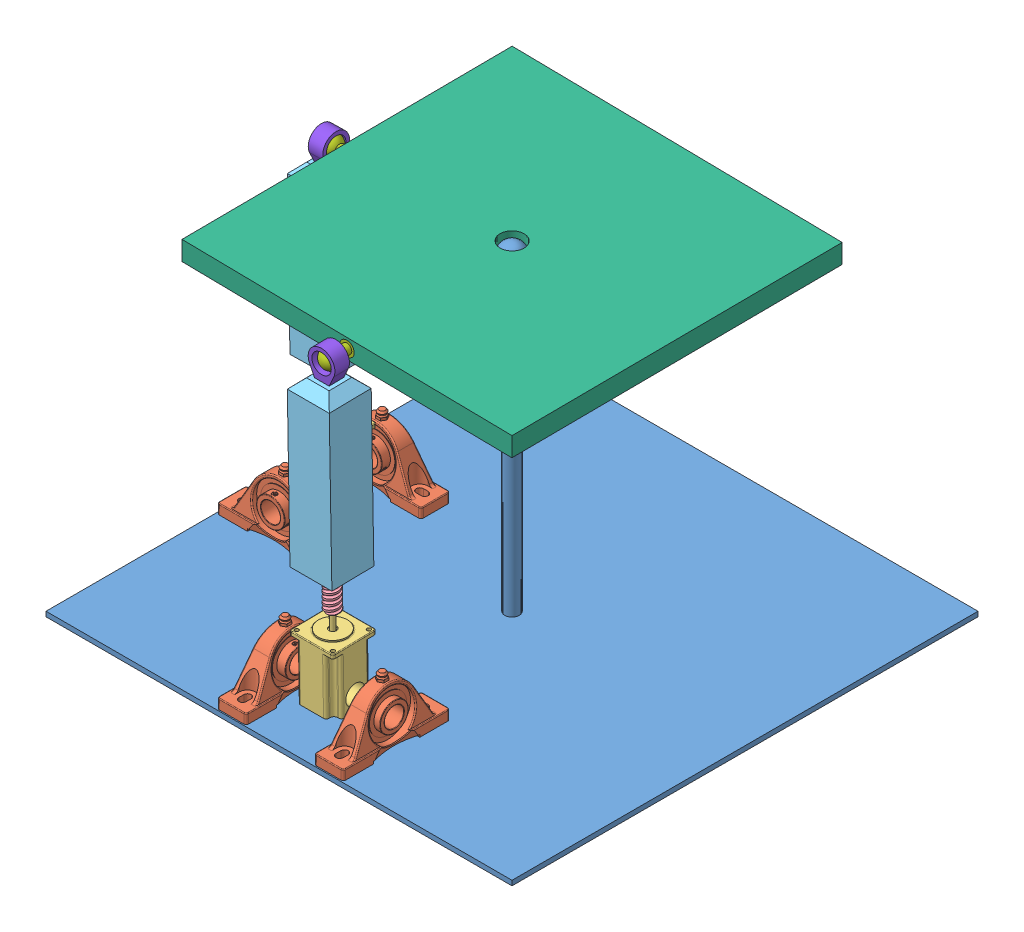
SolidWorks assembly vertical_Assem, configuration Default. Lengths in mm.
Overall size (609.6 435.03 609.6).
16 component instances, 8 part files, 45 mates.
Components (placement in the parent):
- Bottom Platform-1: Bottom Platform [Default] at origin size (609.6 426.08 609.6)
- 7728T560_MOUNTED BALL BEARING WITH CAST IRON HOUSING-1: 7728T560_MOUNTED BALL BEARING WITH CAST IRON HOUSING [7728T56] at (-63.5 42.8625 233.3625) x (0 0 -1) z (1 0 0) size (139.7 80.96 38.1)
- 7728T560_MOUNTED BALL BEARING WITH CAST IRON HOUSING-2: 7728T560_MOUNTED BALL BEARING WITH CAST IRON HOUSING [7728T56] at (-233.3625 42.8625 63.5) size (139.7 80.96 38.1)
- 7728T560_MOUNTED BALL BEARING WITH CAST IRON HOUSING-3: 7728T560_MOUNTED BALL BEARING WITH CAST IRON HOUSING [7728T56] at (-233.3625 42.8625 -63.5) size (139.7 80.96 38.1)
- 7728T560_MOUNTED BALL BEARING WITH CAST IRON HOUSING-4: 7728T560_MOUNTED BALL BEARING WITH CAST IRON HOUSING [7728T56] at (63.5 42.8625 233.3625) x (0 0 1) z (-1 0 0) size (139.7 80.96 38.1)
- 6627T540_POSITION-CONTROL DC MOTOR-2: 6627T540_POSITION-CONTROL DC MOTOR [6627T54] at (0 102.5439 234.3743) x (1 0 0) z (0 0.999856 0.01695) size (57.15 58.17 99.31)
- 6627T540_POSITION-CONTROL DC MOTOR-3: 6627T540_POSITION-CONTROL DC MOTOR [6627T54] at (-234.3457 102.5444 0) x (0 0 -1) z (-0.016472 0.999864 0) size (57.15 58.17 99.31)
- 5966K221_BALL SCREW-3: 5966K221_BALL SCREW [5966K221] at (-234.6846 123.1156 0) x (0.835651 0.013767 0.549088) z (0.016472 -0.999864 0) size (20.38 19.09 157.67)
- 5966K221_BALL SCREW-4: 5966K221_BALL SCREW [5966K221] at (0 123.115 234.723) x (0.768466 0.010846 -0.639798) z (0 -0.999856 -0.01695) size (20.38 19.09 157.67)
- screw_attach-1: screw_attach [Default] at (-235.6215 179.9821 0) x (0 0 1) z (-0.999864 -0.016472 0) size (54.86 215.9 54.86)
- screw_attach-2: screw_attach [Default] at (0 174.7717 235.5987) x (0 0.01695 -0.999856) z (1 0 0) size (54.86 215.9 54.86)
- top_Platform-1: top_Platform [Default] at (0.2375 426.0828 0.1124) x (-0.999888 0.014965 -0.000095) z (-0.000201 -0.007075 0.999975) size (431.8 25.4 431.8)
- ball-2: ball [Default] at (0.0127 412.158 173.3731) x (0.999998 -0.002023 0.000187) z (-0.002021 -0.999973 -0.007076) size (25.4 75.77 25.4)
- hole-1: hole [Default] at (0 348.1018 238.5372) x (0 0.01695 -0.999856) z (1 0 0) size (19.05 81.08 35.03)
- ball-3: ball [Default] at (-173.2881 415.9787 0.006) x (0.011306 0.751263 -0.659906) z (0.009804 0.659833 0.751348) size (25.4 75.77 25.4)
- hole-2: hole [Default] at (-238.477 353.3136 0) x (0.999864 0.016472 0) z (0 0 1) size (19.05 81.08 35.03)
Mates (geometry in assembly coordinates):
- Coincident1: coincident anti-aligned: plane of Bottom Platform-1 through (0 6.35 0) normal (0 1 0); plane of 7728T560_MOUNTED BALL BEARING WITH CAST IRON HOUSING-1 through (-44.45 6.35 203.2) normal (0 -1 0)
- Tangent3: tangent anti-aligned: cylinder of Bottom Platform-1 through (-63.5 6.35 180.975) axis (0 1 0) radius 4.7625; plane of 7728T560_MOUNTED BALL BEARING WITH CAST IRON HOUSING-1 through (-58.7375 6.35 288.925) normal (-1 0 0)
- Tangent5: tangent anti-aligned: cylinder of Bottom Platform-1 through (-63.5 6.35 285.75) axis (0 1 0) radius 4.7625; plane of 7728T560_MOUNTED BALL BEARING WITH CAST IRON HOUSING-1 through (-58.7375 6.35 288.925) normal (-1 0 0)
- Coincident3: coincident: cylinder of Bottom Platform-1 through (-63.5 6.35 180.975) axis (0 1 0) radius 4.7625; moEndPointRef_w of 7728T560_MOUNTED BALL BEARING WITH CAST IRON HOUSING-1
- Coincident4: coincident anti-aligned: plane of Bottom Platform-1 through (0 6.35 0) normal (0 1 0); plane of 7728T560_MOUNTED BALL BEARING WITH CAST IRON HOUSING-2 through (-303.2125 6.35 82.55) normal (0 -1 0)
- Coincident5: coincident anti-aligned: plane of Bottom Platform-1 through (0 6.35 0) normal (0 1 0); plane of 7728T560_MOUNTED BALL BEARING WITH CAST IRON HOUSING-4 through (44.45 6.35 163.5125) normal (0 -1 0)
- Coincident6: coincident anti-aligned: plane of Bottom Platform-1 through (0 6.35 0) normal (0 1 0); plane of 7728T560_MOUNTED BALL BEARING WITH CAST IRON HOUSING-3 through (-303.2125 6.35 -44.45) normal (0 -1 0)
- Tangent6: tangent anti-aligned: cylinder of Bottom Platform-1 through (63.5 6.35 285.75) axis (0 1 0) radius 4.7625; plane of 7728T560_MOUNTED BALL BEARING WITH CAST IRON HOUSING-4 through (68.2625 6.35 282.575) normal (-1 0 0)
- Tangent7: tangent anti-aligned: cylinder of Bottom Platform-1 through (63.5 6.35 180.975) axis (0 1 0) radius 4.7625; plane of 7728T560_MOUNTED BALL BEARING WITH CAST IRON HOUSING-4 through (68.2625 6.35 177.8) normal (-1 0 0)
- Coincident7: coincident: cylinder of Bottom Platform-1 through (63.5 6.35 180.975) axis (0 1 0) radius 4.7625; moEndPointRef_w of 7728T560_MOUNTED BALL BEARING WITH CAST IRON HOUSING-4
- Tangent8: tangent anti-aligned: cylinder of Bottom Platform-1 through (-180.975 6.35 63.5) axis (0 1 0) radius 4.7625; plane of 7728T560_MOUNTED BALL BEARING WITH CAST IRON HOUSING-2 through (-184.15 6.35 58.7375) normal (0 0 1)
- Tangent9: tangent anti-aligned: cylinder of Bottom Platform-1 through (-285.75 6.35 63.5) axis (0 1 0) radius 4.7625; plane of 7728T560_MOUNTED BALL BEARING WITH CAST IRON HOUSING-2 through (-288.925 6.35 58.7375) normal (0 0 1)
- Coincident8: coincident: cylinder of Bottom Platform-1 through (-180.975 6.35 63.5) axis (0 1 0) radius 4.7625; moEndPointRef_w of 7728T560_MOUNTED BALL BEARING WITH CAST IRON HOUSING-2
- Tangent10: tangent anti-aligned: cylinder of Bottom Platform-1 through (-180.975 6.35 -63.5) axis (0 1 0) radius 4.7625; plane of 7728T560_MOUNTED BALL BEARING WITH CAST IRON HOUSING-3 through (-184.15 6.35 -68.2625) normal (0 0 1)
- Tangent11: tangent anti-aligned: cylinder of Bottom Platform-1 through (-285.75 6.35 -63.5) axis (0 1 0) radius 4.7625; plane of 7728T560_MOUNTED BALL BEARING WITH CAST IRON HOUSING-3 through (-288.925 6.35 -68.2625) normal (0 0 1)
- Coincident9: coincident: cylinder of Bottom Platform-1 through (-285.75 6.35 -63.5) axis (0 1 0) radius 4.7625; moEndPointRef_w of 7728T560_MOUNTED BALL BEARING WITH CAST IRON HOUSING-3
- Concentric1: concentric anti-aligned: cylinder of 7728T560_MOUNTED BALL BEARING WITH CAST IRON HOUSING-3 through (-233.3625 42.8625 -79.375) axis (0 0 1) radius 12.7025; cylinder of 6627T540_POSITION-CONTROL DC MOTOR-3 through (-233.3625 42.8625 -28.575) axis (0 0 -1) radius 12.7
- Coincident12: coincident: moEndPointRef_w of 6627T540_POSITION-CONTROL DC MOTOR-3; plane of assembly
- Concentric2: concentric anti-aligned: cylinder of 7728T560_MOUNTED BALL BEARING WITH CAST IRON HOUSING-4 through (79.375 42.8625 233.3625) axis (-1 0 0) radius 12.7025; cylinder of 6627T540_POSITION-CONTROL DC MOTOR-2 through (28.575 42.8625 233.3625) axis (1 0 0) radius 12.7
- Coincident13: coincident: moEndPointRef_w of 6627T540_POSITION-CONTROL DC MOTOR-2; plane of assembly
- Coincident16: coincident anti-aligned: plane of 6627T540_POSITION-CONTROL DC MOTOR-3 through (-237.8592 123.0633 0) normal (-0.016472 0.999864 0); plane of 5966K221_BALL SCREW-3 through (-234.6846 123.1156 0) normal (0.016472 -0.999864 0)
- Concentric5: concentric anti-aligned: cylinder of 6627T540_POSITION-CONTROL DC MOTOR-3 through (-234.6846 123.1156 0) axis (-0.016472 0.999864 0) radius 3.175; cylinder of 5966K221_BALL SCREW-3 through (-237.195 275.4949 0) axis (0.016472 -0.999864 0) radius 9.525
- Concentric6: concentric anti-aligned: cylinder of 6627T540_POSITION-CONTROL DC MOTOR-2 through (0 123.115 234.723) axis (0 0.999856 0.01695) radius 3.175; cylinder of 5966K221_BALL SCREW-4 through (0 275.4931 237.3062) axis (0 -0.999856 -0.01695) radius 9.525
- Coincident17: coincident anti-aligned: plane of 6627T540_POSITION-CONTROL DC MOTOR-2 through (0 123.1688 231.5485) normal (0 0.999856 0.01695); plane of 5966K221_BALL SCREW-4 through (0 123.115 234.723) normal (0 -0.999856 -0.01695)
- Screw1: screw = 12.7 mm aligned: cylinder of 5966K221_BALL SCREW-3 through (-237.195 275.4949 0) axis (0.016472 -0.999864 0) radius 9.525; cylinder of screw_attach-1 through (-235.6215 179.9821 0) axis (0.016472 -0.999864 0) radius 9.525
- Concentric8: concentric anti-aligned: cylinder of 6627T540_POSITION-CONTROL DC MOTOR-3 through (-256.6675 23.425 23.622) axis (-0.016472 0.999864 0) radius 2.54; cylinder of screw_attach-1 through (-259.2403 179.593 23.622) axis (0.016472 -0.999864 0) radius 2.5798
- Screw2: screw = 25.4 mm aligned: cylinder of 5966K221_BALL SCREW-4 through (0 275.4931 237.3062) axis (0 -0.999856 -0.01695) radius 9.525; cylinder of screw_attach-2 through (0 174.7717 235.5987) axis (0 -0.999856 -0.01695) radius 9.525
- Concentric11: concentric anti-aligned: cylinder of 6627T540_POSITION-CONTROL DC MOTOR-2 through (23.622 23.4138 256.6582) axis (0 0.999856 0.01695) radius 2.54; cylinder of screw_attach-2 through (23.622 174.3713 259.2173) axis (0 -0.999856 -0.01695) radius 2.5798
- Concentric18: concentric anti-aligned: cylinder of top_Platform-1 through (0.0041 411.857 215.9171) axis (-0.000201 -0.007075 0.999975) radius 9.525; cylinder of ball-2 through (0.0041 411.857 215.9171) axis (0.000201 0.007075 -0.999975) radius 9.525
- Coincident31: coincident aligned: circle of top_Platform-1; circle of ball-2
- Concentric19: concentric anti-aligned: cylinder of screw_attach-2 through (0 390.6407 239.2583) axis (0 0.999856 0.01695) radius 9.525; cylinder of hole-1 through (0 390.6407 239.2583) axis (0 -0.999856 -0.01695) radius 9.525
- Coincident32: coincident anti-aligned: plane of screw_attach-2 through (0 390.6407 239.2583) normal (0 0.999856 0.01695); plane of hole-1 through (9.525 390.4793 248.7819) normal (0 -0.999856 -0.01695)
- Tangent12: tangent aligned: sphere of ball-2; cylinder of hole-1 through (0 411.4965 249.1382) axis (0 0.01695 -0.999856) radius 12.7
- Concentric20: concentric anti-aligned: cylinder of top_Platform-1 through (-215.8283 416.6154 0.002) axis (-0.999888 0.014965 -0.000095) radius 9.525; cylinder of ball-3 through (-215.8283 416.6154 0.002) axis (0.999888 -0.014965 0.000095) radius 9.525
- Coincident35: coincident aligned: plane of top_Platform-1 through (-216.0617 402.3896 215.8067) normal (-0.999888 0.014965 -0.000095); plane of ball-3 through (-215.8283 416.6154 0.002) normal (-0.999888 0.014965 -0.000095)
- Concentric22: concentric anti-aligned: cylinder of screw_attach-1 through (-239.1779 395.8528 0) axis (-0.016472 0.999864 0) radius 9.525; cylinder of hole-2 through (-239.1779 395.8528 0) axis (0.016472 -0.999864 0) radius 9.525
- Coincident36: coincident anti-aligned: plane of screw_attach-1 through (-239.1779 395.8528 0) normal (-0.016472 0.999864 0); plane of hole-2 through (-248.7016 395.6959 9.525) normal (0.016472 -0.999864 0)
- Tangent13: tangent aligned: sphere of ball-3; cylinder of hole-2 through (-249.0478 416.7133 0) axis (0.999864 0.016472 0) radius 12.7
- Tangent14: tangent aligned: sphere of ball-2; plane of hole-1 through (0 411.4965 249.1382) normal (0 -0.01695 0.999856)
- Tangent15: tangent aligned: sphere of ball-3; plane of hole-2 through (-249.0478 416.7133 0) normal (-0.999864 -0.016472 0)
- Parallel3: parallel aligned: plane of screw_attach-1 through (-211.7496 396.3047 -27.432) normal (0.999864 0.016472 0); plane of hole-2 through (-230.0004 417.0271 0) normal (0.999864 0.016472 0)
- Parallel4: parallel aligned: plane of screw_attach-2 through (-27.432 391.1057 211.8303) normal (0 0.01695 -0.999856); plane of hole-1 through (0 411.8194 230.091) normal (0 0.01695 -0.999856)
- Parallel5: parallel anti-aligned: plane of Bottom Platform-1 through (0 6.35 0) normal (0 1 0); plane of top_Platform-1
- Tangent16: tangent aligned: sphere of Bottom Platform-1; cylinder of top_Platform-1 through (-0.1425 400.6863 -0.0674) axis (0.014964 0.999863 0.007078) radius 15.875
- Tangent18: tangent aligned: sphere of Bottom Platform-1; plane of top_Platform-1 through (0.2375 426.0828 0.1124) normal (0.014964 0.999863 0.007078)
